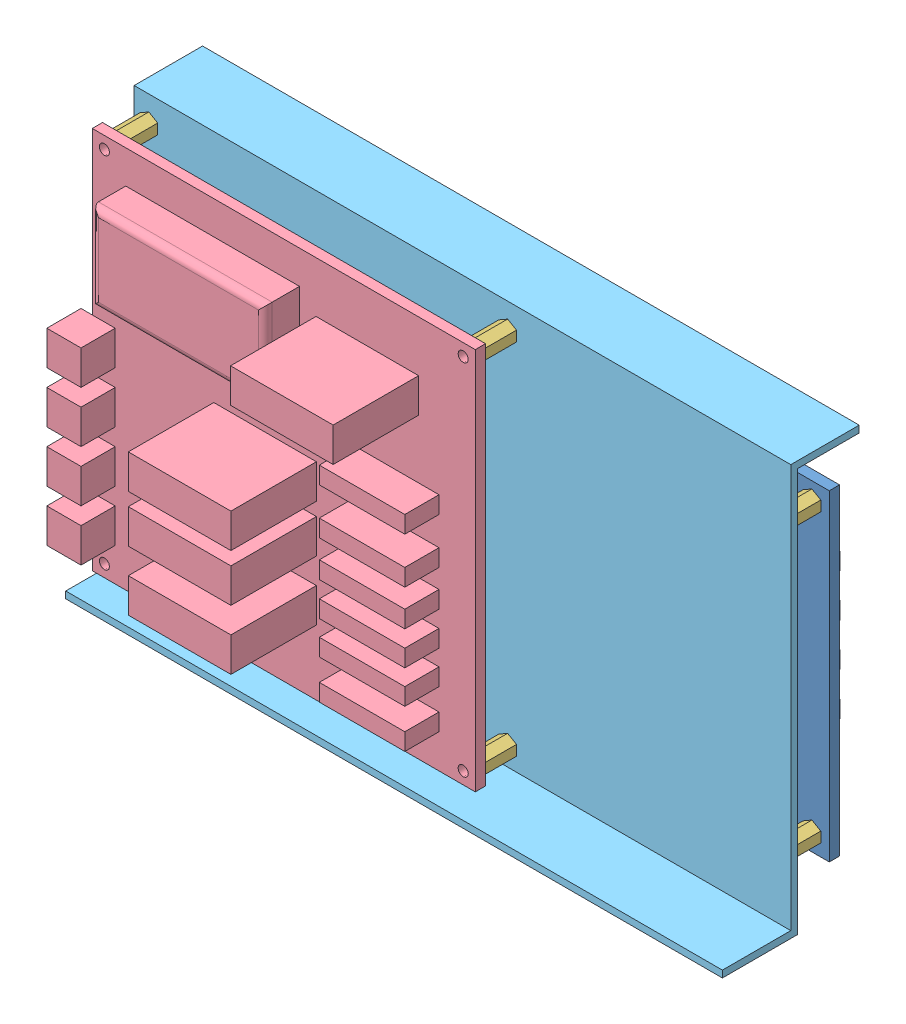
SolidWorks assembly cartes alim IO sur support, configuration Défaut. Lengths in mm.
Overall size (194.54 120 86).
14 component instances, 5 part files, 9 mates.
Components (placement in the parent):
- ensemble_carte_mere_IO_1-1: ensemble_carte_mere_IO_1 [Default] at (-396.8544 187.8446 -91.5753) x (1 0 0) z (0 1 0) size (190.5 46 94)
  - carte_interface_4-1: carte_interface_4 [Default] at (-111.2543 24.11 35.1427) size (190.5 13 94)
  - carte_PIC32_FPGA-1: carte_PIC32_FPGA [Default] at (-78.5043 42.11 28.1427) size (115 23 80)
  - entretoise_M3_L10-1: entretoise_M3_L10 [Default] at (-106.1743 14.11 -53.7773) size (5.2 10 6)
  - entretoise_M3_L10-2: entretoise_M3_L10 [Default] at (-106.1743 14.11 30.0627) size (5.2 10 6)
  - entretoise_M3_L10-3: entretoise_M3_L10 [Default] at (74.1657 14.11 -53.7773) size (5.2 10 6)
  - entretoise_M3_L10-4: entretoise_M3_L10 [Default] at (74.1657 14.11 30.0627) size (5.2 10 6)
- carte_puissance_3_entretoises-1: carte_puissance_3_entretoises [Default] at (-474.519 195.5516 -88.1703) x (-1 0 0) z (0 1 0) size (115.29 38 112)
  - carte_puissance_3-1: carte_puissance_3 [Default] at (-78.4104 -5.515 36.4357) size (115.29 28 112)
  - entretoise_M3_L10-1: entretoise_M3_L10 [Default] at (-74.8604 -15.515 32.8857) size (5.2 10 6)
  - entretoise_M3_L10-2: entretoise_M3_L10 [Default] at (30.0396 -15.515 32.8857) size (5.2 10 6)
  - entretoise_M3_L10-3: entretoise_M3_L10 [Default] at (30.0396 -15.515 -72.0143) size (5.2 10 6)
  - entretoise_M3_L10-4: entretoise_M3_L10 [Default] at (-74.8604 -15.515 -72.0143) size (5.2 10 6)
- Support cartes CM alim-1: Support cartes CM alim [Défaut] at (-508.8586 117.9873 -83.6853) x (0 0 -1) z (1 0 0) size (40 120 192)
Mates (geometry in assembly coordinates):
- Coïncidente1: coincident anti-aligned: plane of carte_puissance_3_entretoises-1/entretoise_M3_L10-2 through (-504.5586 225.4373 -103.6853) normal (0 0 -1); plane of Support cartes CM alim-1 through (-326.1086 117.9873 -103.6853) normal (0 0 1)
- Coïncidente2: coincident anti-aligned: plane of ensemble_carte_mere_IO_1-1/entretoise_M3_L10-2 through (-503.0286 214.9073 -105.6853) normal (0 0 1); plane of Support cartes CM alim-1 through (-326.1086 117.9873 -105.6853) normal (0 0 -1)
- Distance1: distance = 10 mm aligned: plane of carte_puissance_3_entretoises-1/carte_puissance_3-1 through (-508.1086 231.9873 -90.6853) normal (-1 0 0); plane of Support cartes CM alim-1 through (-508.8586 233.9873 -123.6853) normal (-1 0 0)
- Distance2: distance = 10 mm aligned: plane of ensemble_carte_mere_IO_1-1/carte_interface_4-1 through (-508.1086 222.9873 -118.6853) normal (-1 0 0); plane of Support cartes CM alim-1 through (-508.8586 233.9873 -123.6853) normal (-1 0 0)
- Symétrique1: symmetric aligned: plane of carte_puissance_3_entretoises-1/carte_puissance_3-1 through (-396.1086 119.9873 -90.6853) normal (0 -1 0); plane of carte_puissance_3_entretoises-1/carte_puissance_3-1 through (-396.1086 231.9873 -90.6853) normal (0 1 0); plane of assembly through (0 175.9873 0) normal (0 -1 0)
- Symétrique2: symmetric aligned: plane of ensemble_carte_mere_IO_1-1/carte_interface_4-1 through (-508.1086 222.9873 -118.6853) normal (0 1 0); plane of ensemble_carte_mere_IO_1-1/carte_interface_4-1 through (-508.1086 128.9873 -118.6853) normal (0 -1 0); plane of assembly through (0 175.9873 0) normal (0 -1 0)
- Symétrique3: symmetric aligned: plane of ensemble_carte_mere_IO_1-1/carte_interface_4-1 through (-317.6086 222.9873 -118.6853) normal (1 0 0); plane of ensemble_carte_mere_IO_1-1/carte_interface_4-1 through (-508.1086 222.9873 -118.6853) normal (-1 0 0)
- PLAN1: unknown: plane of Support cartes CM alim-1 through (-316.8586 233.9873 -103.6853) normal (0 -1 0); plane of Support cartes CM alim-1 through (-316.8586 117.9873 -83.6853) normal (0 1 0)
- PLAN2: unknown: plane of Support cartes CM alim-1 through (-508.8586 233.9873 -123.6853) normal (-1 0 0); plane of Support cartes CM alim-1 through (-316.8586 233.9873 -123.6853) normal (1 0 0)
